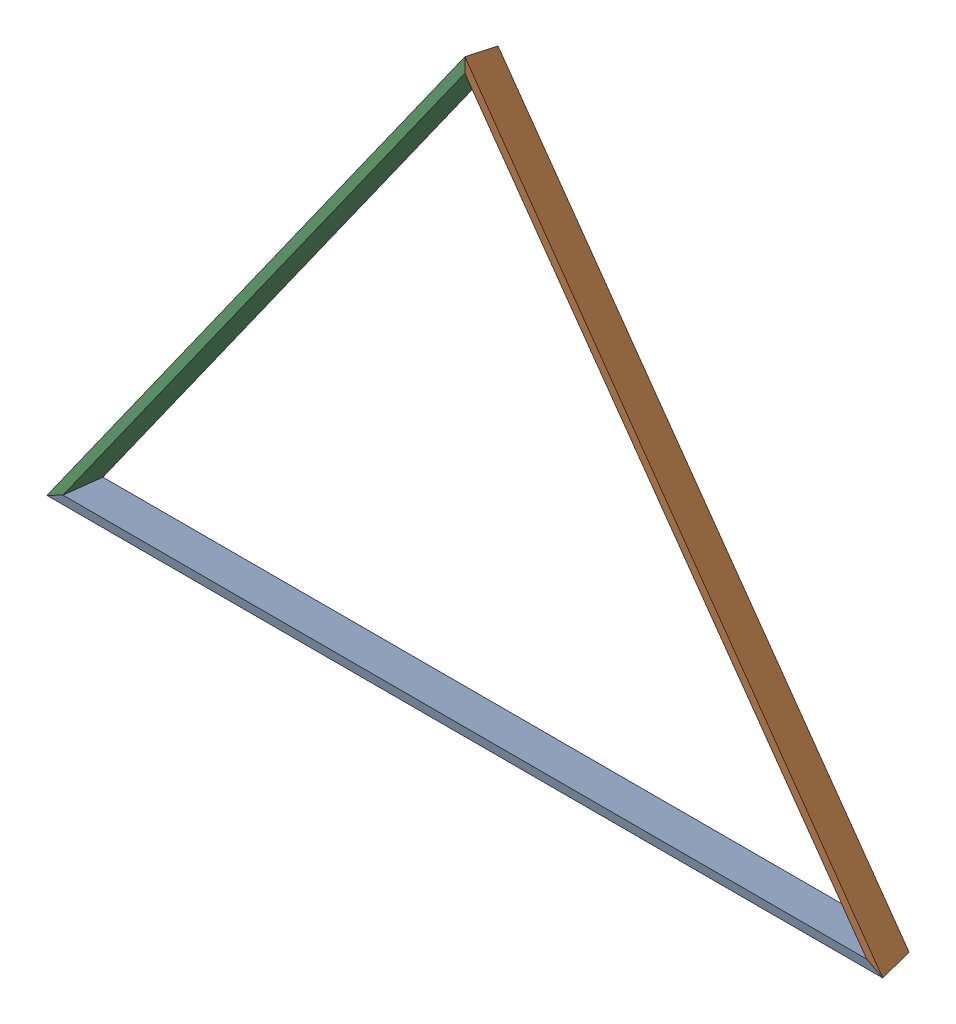
SolidWorks assembly pent_1_1, configuration Default. Lengths in mm.
Overall size (2962.34 3017 2240.7).
3 component instances, 3 part files, 0 mates.
Components (placement in the parent):
- dome-pent_A_1-1: dome-pent_A_1 [Default] at (0 441.1426 -6109.298) x (0.467086 -0.498272 0.730449) z (-0.809017 -0.574201 0.125638) size (1245.79 955.59 2041.73)
- dome-pent_B_1-1: dome-pent_B_1 [Default] at (0 441.1426 -6109.298) x (0.467086 -0.498272 0.730449) z (-0.809017 -0.574201 0.125638) size (1537.41 1660.3 24.8)
- dome-pent_C_1-1: dome-pent_C_1 [Default] at (0 441.1426 -6109.298) x (0.467086 -0.498272 0.730449) z (-0.809017 -0.574201 0.125638) size (368.77 775.55 2041.73)
